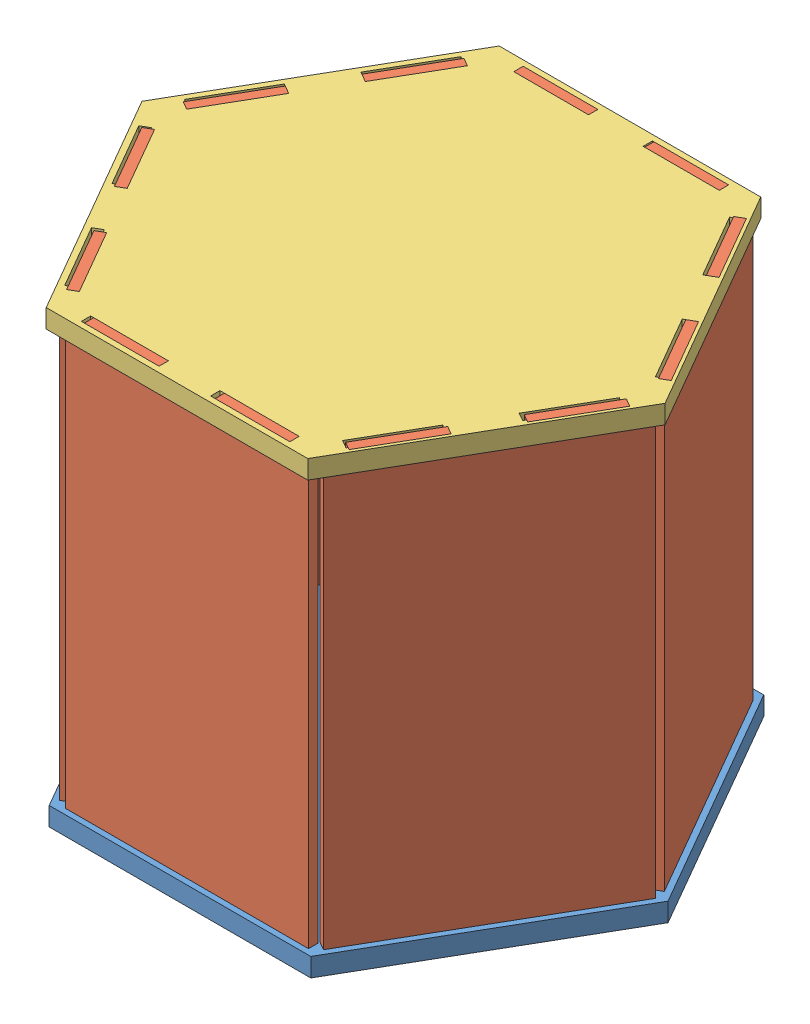
SolidWorks assembly obstacle_assemb, configuration Default. Lengths in mm.
Overall size (178.82 152.4 153.98).
8 component instances, 3 part files, 21 mates.
Components (placement in the parent):
- obstacle_base-1: obstacle_base [Default] at origin size (177.8 6.35 153.98)
- obstacle wall-1: obstacle wall [Default] at (-65.2792 76.2 -37.1024) x (0.5 0 -0.866025) z (0 -1 0) size (82.55 3.17 152.4)
- obstacle wall-2: obstacle wall [Default] at (-64.7712 76.2 37.9823) x (-0.5 0 -0.866025) z (0 -1 0) size (82.55 3.17 152.4)
- obstacle wall-4: obstacle wall [Default] at (0.508 76.2 75.0847) x (-1 0 0) z (0 -1 0) size (82.55 3.17 152.4)
- obstacle wall-6: obstacle wall [Default] at (65.2792 76.2 37.1024) x (-0.5 0 0.866025) z (0 -1 0) size (82.55 3.17 152.4)
- obstacle wall-8: obstacle wall [Default] at (64.7712 76.2 -37.9823) x (0.5 0 0.866025) z (0 -1 0) size (82.55 3.17 152.4)
- obstacle wall-10: obstacle wall [Default] at (-0.508 76.2 -75.0847) x (1 0 0) z (0 -1 0) size (82.55 3.17 152.4)
- obstacle_cover-1: obstacle_cover [Default] at (-1.016 146.05 0) size (177.8 6.35 153.98)
Mates (geometry in assembly coordinates):
- Coincident1: coincident anti-aligned: plane of obstacle_base-1 through (-57.5131 0 -44.2037) normal (-0.866025 0 -0.5); plane of obstacle wall-1 through (-62.5296 76.2 -35.5149) normal (0.866025 0 0.5)
- Coincident2: coincident aligned: plane of obstacle_base-1 through (0 0 0) normal (0 -1 0); plane of obstacle wall-1 through (-83.1671 0 0.2303) normal (0 -1 0)
- Coincident3: coincident anti-aligned: plane of obstacle_base-1 through (-45.0671 0 -65.7608) normal (-0.5 0 0.866025); plane of obstacle wall-1 through (-47.8167 76.2 -67.3483) normal (0.5 0 -0.866025)
- Coincident4: coincident anti-aligned: plane of obstacle_base-1 through (-67.0381 0 27.7059) normal (-0.866025 0 0.5); plane of obstacle wall-2 through (-62.0216 76.2 36.3948) normal (0.866025 0 -0.5)
- Coincident5: coincident aligned: plane of obstacle_base-1 through (0 0 0) normal (0 -1 0); plane of obstacle wall-2 through (-41.3841 0 72.14) normal (0 -1 0)
- Coincident6: coincident anti-aligned: plane of obstacle_base-1 through (-79.4841 0 6.1488) normal (0.5 0 0.866025); plane of obstacle wall-2 through (-82.2337 76.2 7.7363) normal (-0.5 0 -0.866025)
- Coincident7: coincident anti-aligned: plane of obstacle_base-1 through (-9.525 0 71.9097) normal (0 0 1); plane of obstacle wall-4 through (0.508 76.2 71.9097) normal (0 0 -1)
- Coincident8: coincident aligned: plane of obstacle_base-1 through (0 0 0) normal (0 -1 0); plane of obstacle wall-4 through (41.783 0 71.9097) normal (0 -1 0)
- Coincident10: coincident anti-aligned: plane of obstacle_base-1 through (-34.417 0 71.9097) normal (1 0 0); plane of obstacle wall-4 through (-34.417 76.2 75.0847) normal (-1 0 0)
- Coincident11: coincident anti-aligned: plane of obstacle_base-1 through (57.5131 0 44.2037) normal (0.866025 0 0.5); plane of obstacle wall-6 through (62.5296 76.2 35.5149) normal (-0.866025 0 -0.5)
- Coincident12: coincident aligned: plane of obstacle_base-1 through (0 0 0) normal (0 -1 0); plane of obstacle wall-6 through (83.1671 0 -0.2303) normal (0 -1 0)
- Coincident13: coincident anti-aligned: plane of obstacle_base-1 through (45.0671 0 65.7608) normal (0.5 0 -0.866025); plane of obstacle wall-6 through (47.8167 76.2 67.3483) normal (-0.5 0 0.866025)
- Coincident14: coincident anti-aligned: plane of obstacle_base-1 through (67.0381 0 -27.7059) normal (0.866025 0 -0.5); plane of obstacle wall-8 through (62.0216 76.2 -36.3948) normal (-0.866025 0 0.5)
- Coincident15: coincident aligned: plane of obstacle_base-1 through (0 0 0) normal (0 -1 0); plane of obstacle wall-8 through (41.3841 0 -72.14) normal (0 -1 0)
- Coincident16: coincident anti-aligned: plane of obstacle_base-1 through (79.4841 0 -6.1488) normal (-0.5 0 -0.866025); plane of obstacle wall-8 through (82.2337 76.2 -7.7363) normal (0.5 0 0.866025)
- Coincident17: coincident anti-aligned: plane of obstacle_base-1 through (9.525 0 -71.9097) normal (0 0 -1); plane of obstacle wall-10 through (-0.508 76.2 -71.9097) normal (0 0 1)
- Coincident18: coincident aligned: plane of obstacle_base-1 through (0 0 0) normal (0 -1 0); plane of obstacle wall-10 through (-41.783 0 -71.9097) normal (0 -1 0)
- Coincident19: coincident anti-aligned: plane of obstacle_base-1 through (34.417 0 -71.9097) normal (-1 0 0); plane of obstacle wall-10 through (34.417 76.2 -75.0847) normal (1 0 0)
- Coincident20: coincident anti-aligned: plane of obstacle wall-10 through (-0.508 76.2 -71.9097) normal (0 0 1); plane of obstacle_cover-1 through (-10.541 146.05 -71.9097) normal (0 0 -1)
- Coincident21: coincident aligned: plane of obstacle wall-10 through (-41.783 152.4 -71.9097) normal (0 1 0); plane of obstacle_cover-1 through (-1.016 152.4 0) normal (0 1 0)
- Coincident22: coincident anti-aligned: plane of obstacle wall-10 through (-35.433 76.2 -75.0847) normal (-1 0 0); plane of obstacle_cover-1 through (-35.433 146.05 -71.9097) normal (1 0 0)
